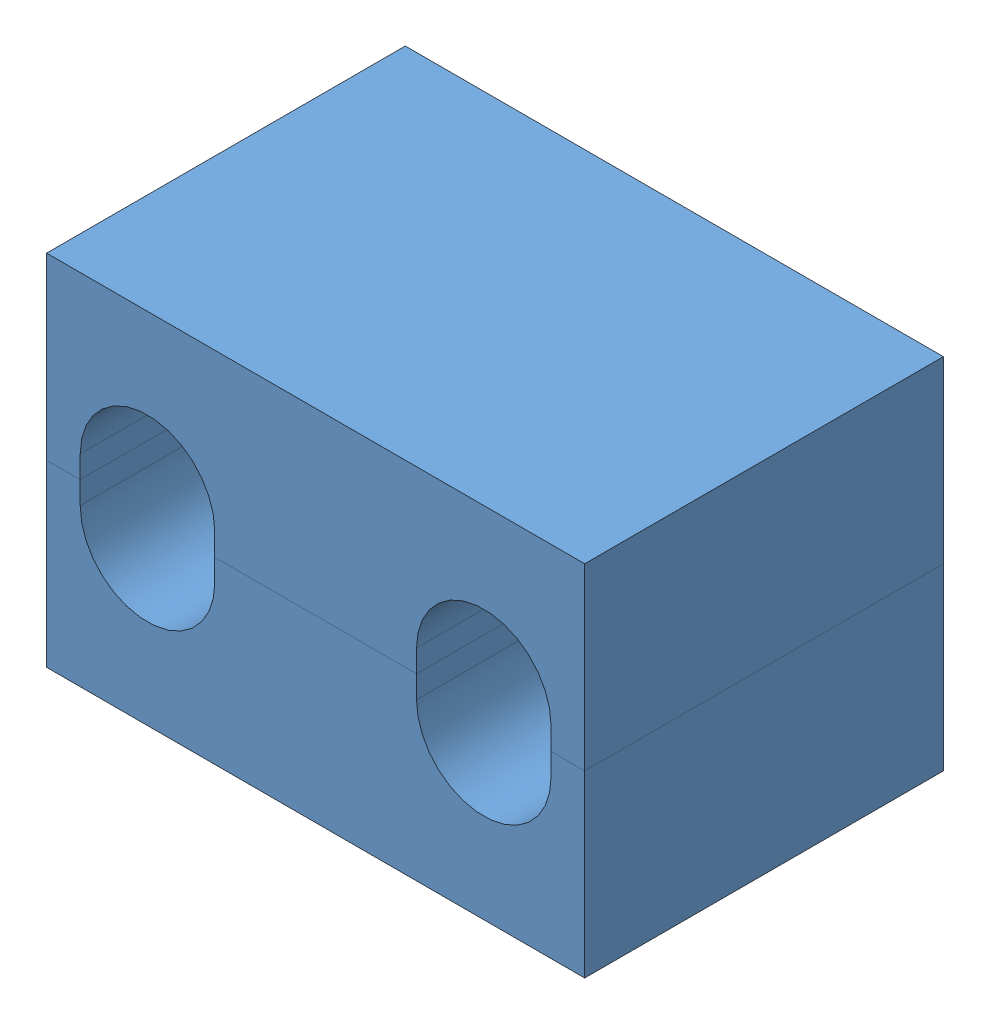
SolidWorks assembly Ensamblaje1, configuration Predeterminado. Lengths in mm.
Overall size (76.2 50.8 50.8).
2 component instances, 1 part files, 3 mates.
Components (placement in the parent):
- Pieza1-1: Pieza1 [Predeterminado] at (-38.8304 -3.0998 50.8) size (76.2 25.4 50.8)
- Pieza1-2: Pieza1 [Predeterminado] at (40.5546 -3.0998 50.8) x (-1 0 0) z (0 0 1) size (76.2 25.4 50.8)
Mates (geometry in assembly coordinates):
- Coincidente1: coincident: plane of Pieza1-1 through (-38.8304 -3.0998 101.6) normal (0 0 1); plane of Pieza1-2 through (40.5546 -15.4578 101.6) normal (0 0 1)
- Coincidente2: coincident: plane of Pieza1-1 through (-37.2379 -28.4998 101.6) normal (-1 0 0); plane of Pieza1-2 through (-37.2379 9.9422 101.6) normal (-1 0 0)
- Coincidente4: coincident anti-aligned: plane of Pieza1-1 through (-37.2379 -3.0998 50.8) normal (0 -1 0); plane of Pieza1-2 through (38.9621 -3.0998 50.8) normal (0 1 0)
